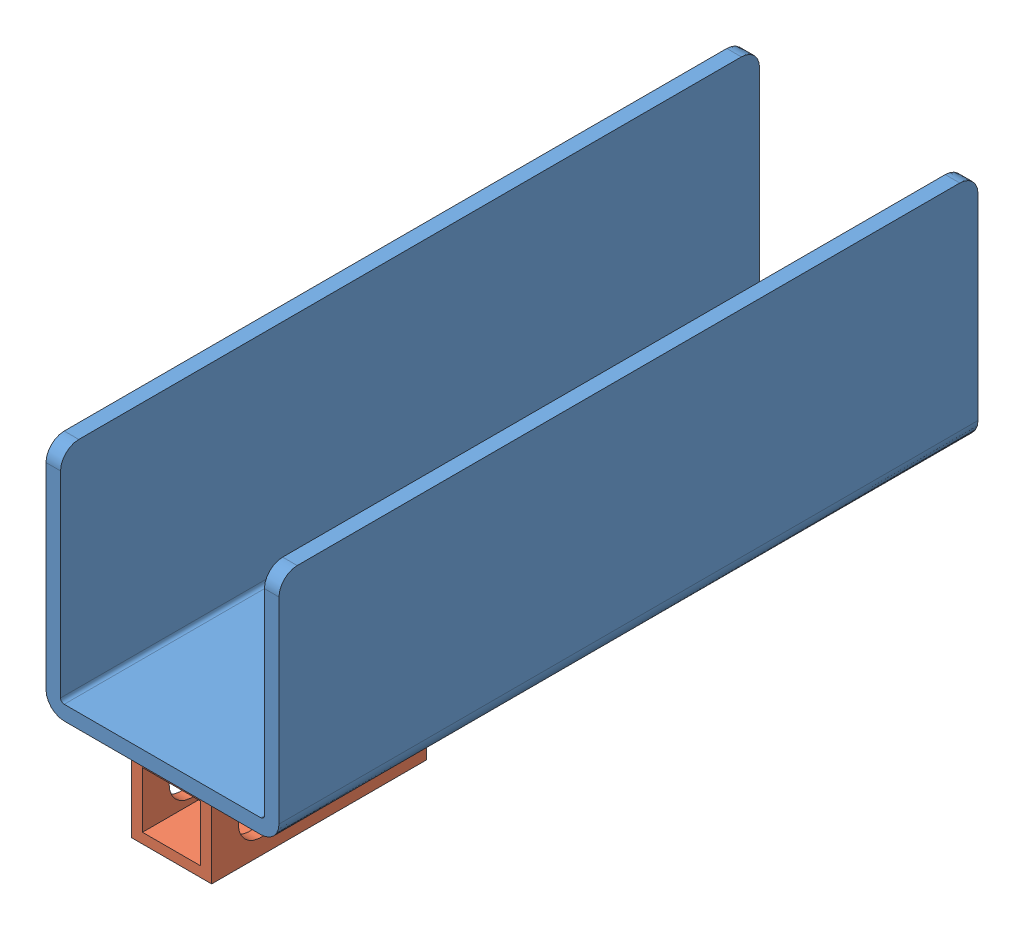
SolidWorks assembly Mantis step 9, configuration Simplified. Lengths in mm.
Overall size (32 42.5 96).
6 component instances, 4 part files, 15 mates.
Components (placement in the parent):
- Channel 96mm-1: Channel 96mm [Simplified] at origin size (32 32 96)
- LEGO HPC-1: LEGO HPC [Simplified] at (0 0 32) x (-1 0 0) z (0 0 1) size (24.2 10.5 29.5)
- Screw SHCS 6-32 x 0.5-1: Screw SHCS 6-32 x 0.5 [PreviewCfg] at (8 -4.7052 32) x (0 1 0) z (0 0 1) size (16.21 5.74 5.74) (suppressed, hidden)
- Screw SHCS 6-32 x 0.5-2: Screw SHCS 6-32 x 0.5 [PreviewCfg] at (-8 -4.7052 32) x (0 1 0) z (0 0 1) size (16.21 5.74 5.74) (suppressed, hidden)
- Nut Hex 6-32 KEP lock-1: Nut Hex 6-32 KEP lock [90675A007] at (-8 4.1828 32) size (8.74 3.59 9.17) (suppressed, hidden)
- Nut Hex 6-32 KEP lock-2: Nut Hex 6-32 KEP lock [90675A007] at (8 4.1828 32) size (8.74 3.59 9.17) (suppressed, hidden)
Mates (geometry in assembly coordinates):
- Concentric5: concentric anti-aligned: cylinder of LEGO HPC-1 through (0 -10.5 32) axis (0 1 0) radius 3.1; cylinder of Channel 96mm-1 through (0 32 32) axis (0 -1 0) radius 4
- Coincident3: coincident anti-aligned: plane of Channel 96mm-1 through (-13.5 0 48) normal (0 -1 0); plane of LEGO HPC-1 through (0 0 32) normal (0 1 0)
- Parallel1: parallel anti-aligned: plane of LEGO HPC-1; plane of assembly through (0 0 0) normal (1 0 0)
- Concentric7: concentric anti-aligned: circle of LEGO HPC-1; cylinder of Screw SHCS 6-32 x 0.5-2 through (-8 -36.4552 32) axis (0 -1 0) radius 1.7526
- Concentric8: concentric anti-aligned: cylinder of LEGO HPC-1 through (8 -1.2 32) axis (0 1 0) radius 1.75; cylinder of Screw SHCS 6-32 x 0.5-1 through (8 -36.4552 32) axis (0 -1 0) radius 1.7526
- Coincident4: coincident anti-aligned: plane of LEGO HPC-1 through (0 -1.2 32) normal (0 -1 0); plane of Screw SHCS 6-32 x 0.5-1 through (5.1298 -1.2 32) normal (0 1 0)
- Coincident5: coincident anti-aligned: plane of LEGO HPC-1 through (0 -1.2 32) normal (0 -1 0); plane of Screw SHCS 6-32 x 0.5-2 through (-10.8702 -1.2 32) normal (0 1 0)
- Concentric9: concentric anti-aligned: cylinder of Screw SHCS 6-32 x 0.5-1 through (8 -36.4552 32) axis (0 -1 0) radius 1.7526; circle of Nut Hex 6-32 KEP lock-2
- Concentric10: concentric anti-aligned: cylinder of Screw SHCS 6-32 x 0.5-2 through (-8 -36.4552 32) axis (0 -1 0) radius 1.7526; circle of Nut Hex 6-32 KEP lock-1
- Coincident6: coincident aligned: plane of Channel 96mm-1 through (13.5 2 48) normal (0 1 0); circle of Nut Hex 6-32 KEP lock-2
- Coincident7: coincident aligned: plane of Channel 96mm-1 through (13.5 2 48) normal (0 1 0); circle of Nut Hex 6-32 KEP lock-1
- Parallel2: parallel aligned: plane of assembly through (0 0 0) normal (1 0 0); plane of Nut Hex 6-32 KEP lock-2 through (8 4.1828 32) normal (1 0 0)
- Parallel3: parallel aligned: plane of assembly through (0 0 0) normal (1 0 0); plane of Nut Hex 6-32 KEP lock-1 through (-8 4.1828 32) normal (1 0 0)
- Parallel4: parallel anti-aligned: plane of assembly through (0 0 0) normal (1 0 0); plane of Screw SHCS 6-32 x 0.5-2
- Parallel5: parallel anti-aligned: plane of assembly through (0 0 0) normal (1 0 0); plane of Screw SHCS 6-32 x 0.5-1
